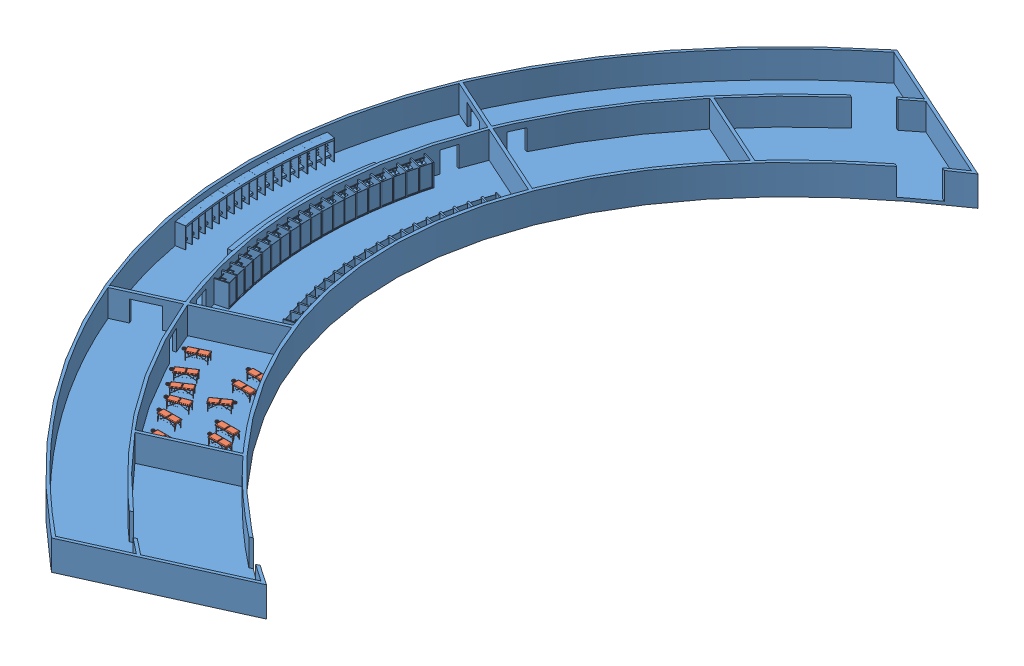
SolidWorks assembly locker assembly, configuration Default. Lengths in mm.
Overall size (41124.66 3048 86733.57).
12 component instances, 2 part files, 12 mates.
Components (placement in the parent):
- locker-1: locker [Default] at (43867.4685 127729.3397 184507.339) size (41124.66 3048 86733.57)
- table-1: table [Predeterminado] at (-54209.9206 128734.1397 201834.8002) x (0.900913 0 -0.434) z (0.434 0 0.900913) size (2173.63 1215.46 1335.53)
- table-2: table [Predeterminado] at (-50806.9628 128734.1397 207124.448) x (0.932268 0 -0.361768) z (0.361768 0 0.932268) size (2173.63 1215.46 1335.53)
- table-3: table [Predeterminado] at (-51956.2036 128734.1397 205687.2332) x (0.836971 0 -0.547247) z (0.547247 0 0.836971) size (2173.63 1215.46 1335.53)
- table-6: table [Predeterminado] at (-48394.3067 128734.1397 211180.6752) size (2173.63 1215.46 1335.53)
- table-7: table [Predeterminado] at (-49945.8211 128734.1397 209020.6231) size (2173.63 1215.46 1335.53)
- table-8: table [Predeterminado] at (-53092.676 128734.1397 204162.5346) x (0.837352 0 -0.546664) z (0.546664 0 0.837352) size (2173.63 1215.46 1335.53)
- table-9: table [Predeterminado] at (-48665.671 128734.1397 202616.6204) size (2173.63 1215.46 1335.53)
- table-10: table [Predeterminado] at (-45914.159 128734.1397 207088.8301) size (2173.63 1215.46 1335.53)
- table-11: table [Predeterminado] at (-48973.2612 128734.1397 200831.197) size (2173.63 1215.46 1335.53)
- table-12: table [Predeterminado] at (-48641.4135 128734.1397 205119.6802) x (-0.818134 0 0.575028) z (-0.575028 0 -0.818134) size (2173.63 1215.46 1335.53)
- table-13: table [Predeterminado] at (-45195.0968 128734.1397 208554.7807) size (2173.63 1215.46 1335.53)
Mates (geometry in assembly coordinates):
- Coincident1: coincident anti-aligned: plane of locker-1 through (43867.4685 128034.1397 184507.339) normal (0 1 0); plane of table-1 through (-54209.9206 128034.1397 201834.8002) normal (0 -1 0)
- Coincident3: coincident anti-aligned: plane of locker-1 through (43867.4685 128034.1397 184507.339) normal (0 1 0); plane of table-2 through (-50806.9628 128034.1397 207124.448) normal (0 -1 0)
- Coincident4: coincident anti-aligned: plane of locker-1 through (43867.4685 128034.1397 184507.339) normal (0 1 0); plane of table-8 through (-53092.676 128034.1397 204162.5346) normal (0 -1 0)
- Coincident5: coincident anti-aligned: plane of locker-1 through (43867.4685 128034.1397 184507.339) normal (0 1 0); plane of table-6 through (-48394.3067 128034.1397 211180.6752) normal (0 -1 0)
- Coincident6: coincident aligned: plane of table-3 through (-51956.2036 128034.1397 205687.2332) normal (0 -1 0); plane of table-7 through (-49945.8211 128034.1397 209020.6231) normal (0 -1 0)
- Coincident7: coincident anti-aligned: plane of locker-1 through (43867.4685 128034.1397 184507.339) normal (0 1 0); plane of table-3 through (-51956.2036 128034.1397 205687.2332) normal (0 -1 0)
- Coincident8: coincident anti-aligned: plane of locker-1 through (43867.4685 128034.1397 184507.339) normal (0 1 0); plane of table-7 through (-49945.8211 128034.1397 209020.6231) normal (0 -1 0)
- Coincident9: coincident anti-aligned: plane of locker-1 through (43867.4685 128034.1397 184507.339) normal (0 1 0); plane of table-13 through (-45195.0968 128034.1397 208554.7807) normal (0 -1 0)
- Coincident11: coincident anti-aligned: plane of locker-1 through (43867.4685 128034.1397 184507.339) normal (0 1 0); plane of table-12 through (-48641.4135 128034.1397 205119.6802) normal (0 -1 0)
- Coincident12: coincident anti-aligned: plane of locker-1 through (43867.4685 128034.1397 184507.339) normal (0 1 0); plane of table-10 through (-45914.159 128034.1397 207088.8301) normal (0 -1 0)
- Coincident13: coincident anti-aligned: plane of locker-1 through (43867.4685 128034.1397 184507.339) normal (0 1 0); plane of table-9 through (-48665.671 128034.1397 202616.6204) normal (0 -1 0)
- Coincident14: coincident anti-aligned: plane of locker-1 through (43867.4685 128034.1397 184507.339) normal (0 1 0); plane of table-11 through (-48973.2612 128034.1397 200831.197) normal (0 -1 0)
